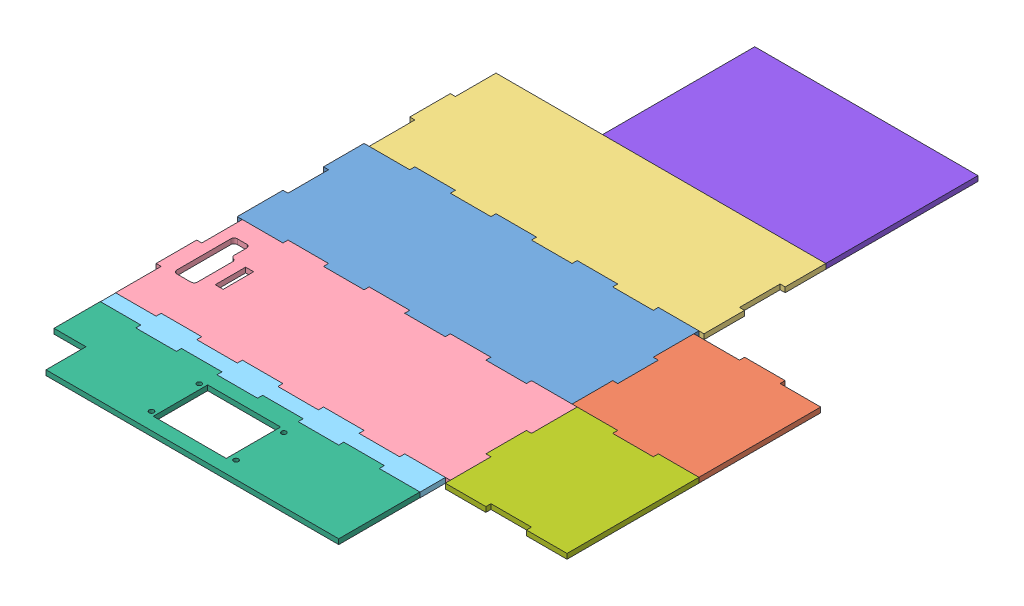
SolidWorks assembly Wire Housing Print part 1, configuration Default. Lengths in mm.
Overall size (285.75 3.17 396.9).
8 component instances, 8 part files, 20 mates.
Components (placement in the parent):
- electronics box topbottom-2: electronics box topbottom [Default] at (79.3352 110.2972 160.6969) x (1 0 0) z (0 -1 0) size (209.55 82.55 3.17)
- end parts of box (b)-2: end parts of box (b) [Default] at (222.2102 110.2972 160.6969) x (-1 0 0) z (0 -1 0) size (79.38 82.55 3.17)
- panel for wall 2-1: panel for wall 2 [Default] at (79.3352 110.2972 81.3219) x (1 0 0) z (0 -1 0) size (209.55 79.38 3.17)
- panel for wall-1: panel for wall [Default] at (79.3352 110.2972 240.0719) x (1 0 0) z (0 -1 0) size (209.55 82.55 3.17)
- spacer for top of printer-1: spacer for top of printer [Default] at (79.3352 110.2972 286.1008) x (1 0 0) z (0 -1 0) size (203.2 15.88 3.17)
- UI-for-front-1: UI-for-front [Default] at (79.3352 107.1222 319.4469) x (1 0 0) z (0 1 0) size (203.2 53.97 3.17)
- end parts of box-3: end parts of box [Default] at (222.2102 110.2972 240.0719) x (0 0 -1) z (0 -1 0) size (82.55 79.38 3.17)
- Wiring Cover-1: Wiring Cover [Default] at (114.2602 107.1222 -4.4158) size (139.7 3.17 95.28)
Mates (geometry in assembly coordinates):
- Coincident1: coincident aligned: plane of electronics box topbottom-2 through (79.3352 110.2972 160.6969) normal (0 1 0); plane of panel for wall 2-1 through (79.3352 110.2972 81.3219) normal (0 1 0)
- Coincident4: coincident aligned: plane of electronics box topbottom-2 through (79.3352 110.2972 160.6969) normal (0 1 0); plane of panel for wall-1 through (79.3352 110.2972 240.0719) normal (0 1 0)
- Coincident5: coincident aligned: plane of panel for wall-1 through (79.3352 110.2972 240.0719) normal (0 1 0); plane of spacer for top of printer-1 through (79.3352 110.2972 286.1008) normal (0 1 0)
- Coincident6: coincident anti-aligned: plane of panel for wall-1 through (-22.2648 107.1222 278.1719) normal (0 0 1); plane of spacer for top of printer-1 through (-22.1538 107.1222 278.1719) normal (0 0 -1)
- Coincident7: coincident anti-aligned: plane of electronics box topbottom-2 through (-22.2648 107.1222 198.7969) normal (0 0 1); plane of panel for wall-1 through (180.9352 110.2972 198.7969) normal (0 0 -1)
- Coincident8: coincident anti-aligned: plane of electronics box topbottom-2 through (180.9352 110.2972 119.4219) normal (0 0 -1); plane of panel for wall 2-1 through (-22.2648 107.1222 119.4219) normal (0 0 1)
- Coincident11: coincident anti-aligned: plane of electronics box topbottom-2 through (155.5352 110.2972 201.9719) normal (1 0 0); plane of panel for wall-1 through (155.5352 110.2972 201.9719) normal (-1 0 0)
- Coincident12: coincident anti-aligned: plane of end parts of box (b)-2 through (260.3102 107.1222 198.7969) normal (0 0 1); plane of panel for wall-1 through (180.9352 110.2972 198.7969) normal (0 0 -1)
- Coincident13: coincident anti-aligned: plane of electronics box topbottom-2 through (180.9352 107.1222 122.5969) normal (1 0 0); plane of end parts of box (b)-2 through (180.9352 110.2972 122.5969) normal (-1 0 0)
- Coincident14: coincident aligned: plane of electronics box topbottom-2 through (79.3352 110.2972 160.6969) normal (0 1 0); plane of end parts of box (b)-2 through (222.2102 110.2972 160.6969) normal (0 1 0)
- Coincident19: coincident anti-aligned: plane of panel for wall-1 through (3.1352 110.2972 278.1719) normal (1 0 0); plane of spacer for top of printer-1 through (3.1352 110.2972 278.1546) normal (-1 0 0)
- Coincident20: coincident anti-aligned: plane of panel for wall-1 through (180.9352 107.1222 201.9719) normal (1 0 0); plane of end parts of box-3 through (180.9352 110.2972 252.7719) normal (-1 0 0)
- Coincident21: coincident aligned: plane of electronics box topbottom-2 through (79.3352 110.2972 160.6969) normal (0 1 0); plane of end parts of box-3 through (222.2102 110.2972 240.0719) normal (0 1 0)
- Coincident22: coincident anti-aligned: plane of panel for wall-1 through (180.9352 110.2972 252.7719) normal (0 0 -1); plane of end parts of box-3 through (184.1102 110.2972 252.7719) normal (0 0 1)
- Coincident23: coincident anti-aligned: plane of spacer for top of printer-1 through (104.7352 110.2972 294.0469) normal (-1 0 0); plane of UI-for-front-1 through (104.7352 107.1222 294.0469) normal (1 0 0)
- Coincident24: coincident anti-aligned: plane of spacer for top of printer-1 through (-22.1538 107.1222 294.0469) normal (0 0 1); plane of UI-for-front-1 through (-22.2648 110.2972 294.0469) normal (0 0 -1)
- Coincident25: coincident aligned: plane of panel for wall-1 through (79.3352 110.2972 240.0719) normal (0 1 0); plane of UI-for-front-1 through (79.3352 110.2972 319.4469) normal (0 1 0)
- Coincident26: coincident aligned: plane of panel for wall 2-1 through (79.3352 110.2972 81.3219) normal (0 1 0); plane of Wiring Cover-1 through (114.2602 110.2972 -4.4158) normal (0 1 0)
- Coincident27: coincident anti-aligned: plane of panel for wall 2-1 through (-22.2648 107.1222 43.2219) normal (0 0 -1); plane of Wiring Cover-1 through (44.4102 110.2972 43.2219) normal (0 0 1)
- Coincident28: coincident aligned: plane of panel for wall 2-1 through (184.1102 110.2972 43.2219) normal (1 0 0); plane of Wiring Cover-1 through (184.1102 110.2972 43.2219) normal (1 0 0)
